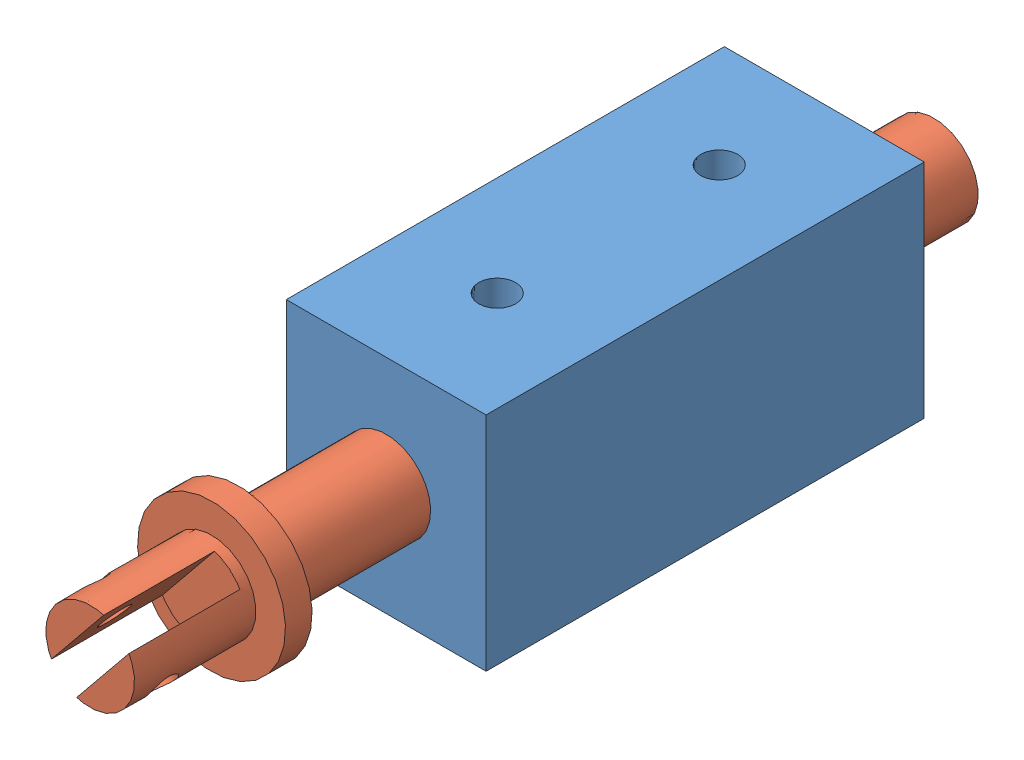
SolidWorks assembly ASSY_SOLENOID, configuration Default. Lengths in mm.
Overall size (14.07 15 57).
2 component instances, 2 part files, 2 mates.
Components (placement in the parent):
- SOLENOID_CASE-1: SOLENOID_CASE [Default] at origin size (13.5 15 29.6)
- SOLENOID_SLIDER-1: SOLENOID_SLIDER [Default] at (0 0 6.3) x (-0.775642 0.631174 0) z (0 0 1) size (10 10 57)
Mates (geometry in assembly coordinates):
- Concentric1: concentric aligned: cylinder of SOLENOID_CASE-1 through (0 0 -14) axis (0 0 1) radius 3; cylinder of SOLENOID_SLIDER-1 through (0 0 -2.2) axis (0 0 1) radius 3
- LimitDistance1: limit distance = 10 mm anti-aligned: plane of SOLENOID_CASE-1 through (0 0 14.8) normal (0 0 1); plane of SOLENOID_SLIDER-1 through (0 0 24.8) normal (0 0 -1)
